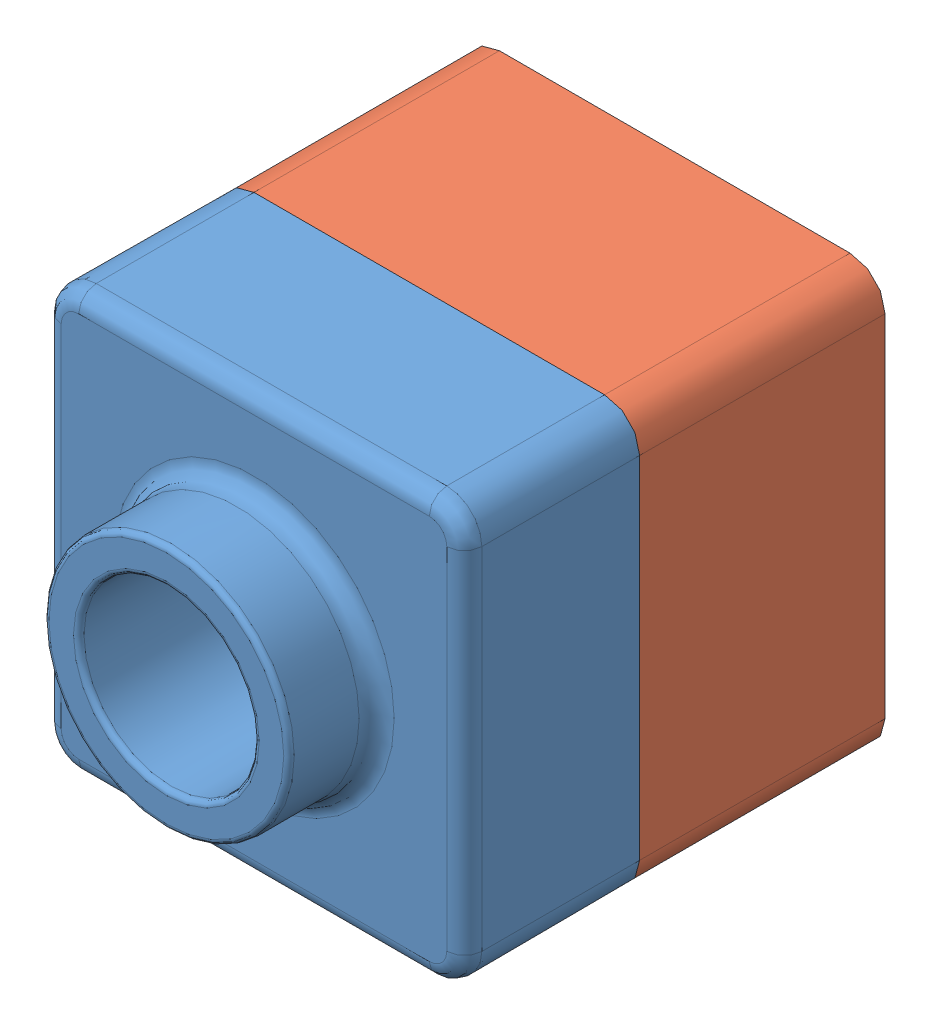
SolidWorks assembly practice assembly, configuration Default. Lengths in mm.
Overall size (120 120 145).
2 component instances, 2 part files, 3 mates.
Components (placement in the parent):
- practice part 1-1: practice part 1 [Default] at (38.8097 66.5143 92.6235) size (120 120 75)
- practice part 2-1: practice part 2 [Default] at (38.8097 66.5143 22.6235) size (120 120 90)
Mates (geometry in assembly coordinates):
- Coincident1: coincident: line of practice part 1-1 through (148.8097 186.5143 92.6235) axis (-1 0 0); line of practice part 2-1 through (148.8097 186.5143 92.6235) axis (-1 0 0)
- Coincident7: coincident: plane of practice part 1-1 through (158.8097 66.5143 142.6235) normal (1 0 0); plane of practice part 2-1 through (158.8097 66.2954 111.2627) normal (1 0 0)
- Coincident8: coincident aligned: plane of practice part 1-1 through (38.8097 186.5143 142.6235) normal (0 1 0); plane of practice part 2-1 through (38.8097 186.5143 112.6235) normal (0 1 0)
